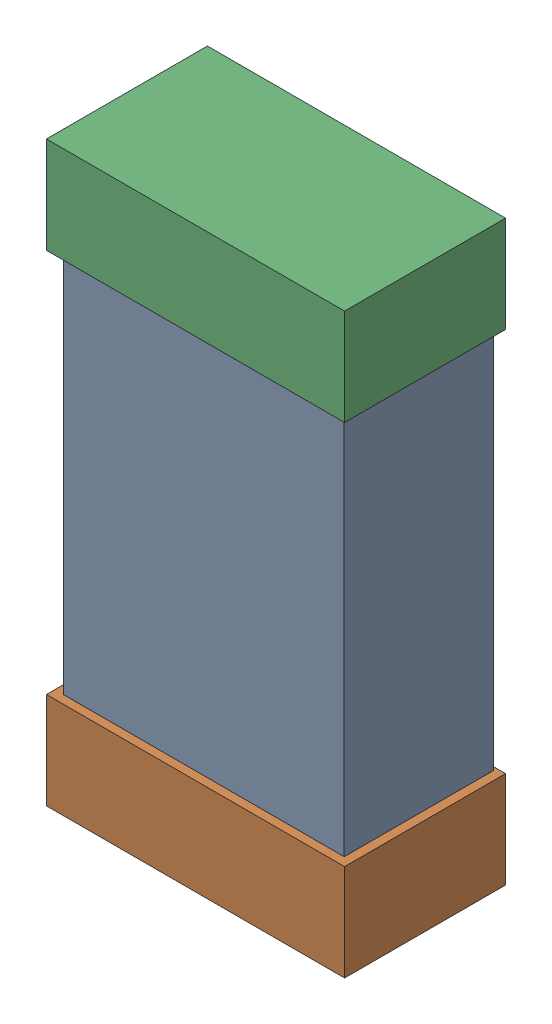
SolidWorks assembly C26, configuration Default. Lengths in mm.
Overall size (0.85 1.65 0.46).
6 component instances, 2 part files, 0 mates.
Components (placement in the parent):
- 432124816_36-1: 432124816_36 [Default] at (29.5001 60.7501 -0.8615) size (0.8 1.5 0.42)
  - Extruded (1)-1: Extruded (1) [Default] at origin size (0.8 1.5 0.42)
- 432138512_72-1: 432138512_72 [Default] at (29.5001 60.0643 -0.8715) size (0.85 0.28 0.46)
  - Extruded-1: Extruded [Default] at origin size (0.85 0.28 0.46)
- 432138512_73-1: 432138512_73 [Default] at (29.5001 61.4359 -0.8715) size (0.85 0.28 0.46)
  - Extruded-1: Extruded [Default] at origin size (0.85 0.28 0.46)
